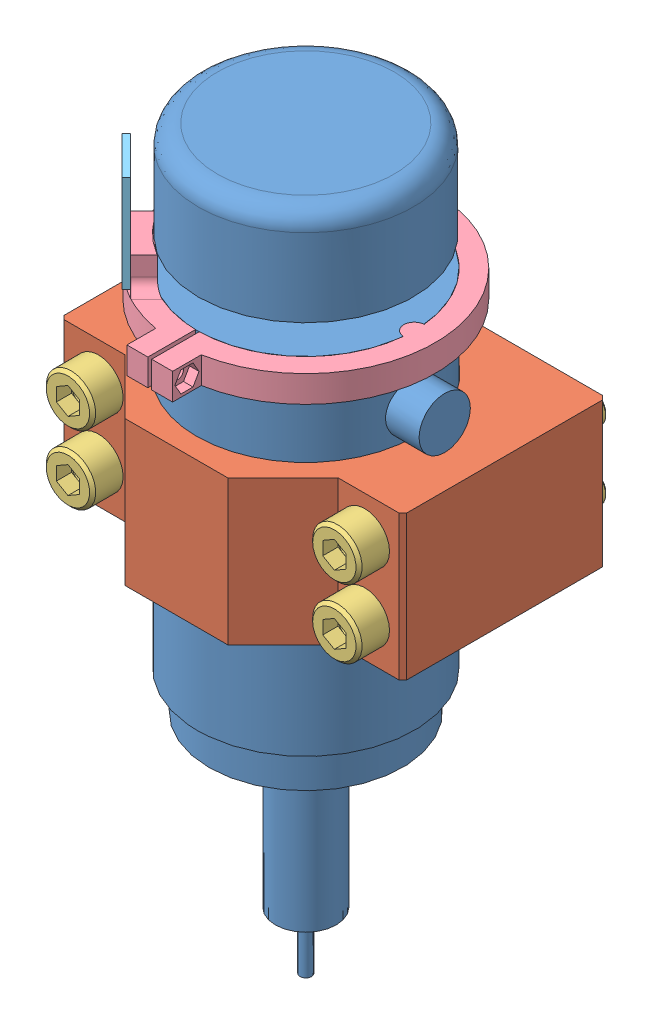
SolidWorks assembly Spindle Assembly, configuration Default. Lengths in mm.
Overall size (90 193.5 81.5).
8 component instances, 5 part files, 14 mates.
Components (placement in the parent):
- E240-Spindle-1: E240-Spindle [Default] at (-79.402 33.4299 34.999) size (73 193.5 57)
- Spindle-Clamp-1: Spindle-Clamp [Default] at (-79.402 35.9299 34.999) x (1 0 0) z (0 -1 0) size (90 68 38)
- socket head cap screw_am-1: socket head cap screw_am [B18.3.1M - 8 x 1.25 x 60 Hex SHCS -- 60NHX] at (-114.402 26.9299 62.499) x (0 0 -1) z (1 0 0) size (68 13 13)
- socket head cap screw_am-2: socket head cap screw_am [B18.3.1M - 8 x 1.25 x 60 Hex SHCS -- 60NHX] at (-114.402 44.9299 62.499) x (0 0 -1) z (1 0 0) size (68 13 13)
- socket head cap screw_am-3: socket head cap screw_am [B18.3.1M - 8 x 1.25 x 60 Hex SHCS -- 60NHX] at (-44.402 44.9299 62.499) x (0 0 -1) z (1 0 0) size (68 13 13)
- socket head cap screw_am-4: socket head cap screw_am [B18.3.1M - 8 x 1.25 x 60 Hex SHCS -- 60NHX] at (-44.402 26.9299 62.499) x (0 0 -1) z (1 0 0) size (68 13 13)
- Tachometer-Mount-1: Tachometer-Mount [Default] at (-79.402 71.9299 34.999) size (68 15 75)
- Tachometer-PCB-1: Tachometer-PCB [Default] at (-103.5839 91.8199 59.1809) x (-0.707107 0 -0.707107) z (0.707107 0 -0.707107) size (14.22 25.4 1.6)
Mates (geometry in assembly coordinates):
- Concentric3: concentric anti-aligned: circle of Spindle-Clamp-1; circle of E240-Spindle-1
- Distance3: distance = 29 mm aligned: plane of Spindle-Clamp-1 through (-79.402 16.9299 34.999) normal (0 -1 0); plane of E240-Spindle-1 through (-79.402 -12.0701 34.999) normal (0 -1 0)
- Concentric4: concentric aligned: cylinder of Spindle-Clamp-1 through (-114.402 26.9299 68.999) axis (0 0 1) radius 4.2; cylinder of socket head cap screw_am-1 through (-114.402 26.9299 94.249) axis (0 0 1) radius 6.5
- Coincident1: coincident anti-aligned: plane of Spindle-Clamp-1 through (-124.402 54.9299 54.499) normal (0 0 1); plane of socket head cap screw_am-1 through (-114.402 33.4299 54.499) normal (0 0 -1)
- Concentric5: concentric aligned: cylinder of Spindle-Clamp-1 through (-114.402 44.9299 68.999) axis (0 0 1) radius 4.2; cylinder of socket head cap screw_am-2 through (-114.402 44.9299 94.249) axis (0 0 1) radius 6.5
- Coincident2: coincident anti-aligned: plane of Spindle-Clamp-1 through (-124.402 54.9299 54.499) normal (0 0 1); plane of socket head cap screw_am-2 through (-114.402 51.4299 54.499) normal (0 0 -1)
- Concentric6: concentric aligned: cylinder of Spindle-Clamp-1 through (-44.402 44.9299 68.999) axis (0 0 1) radius 4.2; cylinder of socket head cap screw_am-3 through (-44.402 44.9299 94.249) axis (0 0 1) radius 6.5
- Coincident3: coincident anti-aligned: plane of Spindle-Clamp-1 through (-34.402 54.9299 54.499) normal (0 0 1); plane of socket head cap screw_am-3 through (-44.402 51.4299 54.499) normal (0 0 -1)
- Concentric7: concentric aligned: cylinder of Spindle-Clamp-1 through (-44.402 26.9299 68.999) axis (0 0 1) radius 4.2; cylinder of socket head cap screw_am-4 through (-44.402 26.9299 94.249) axis (0 0 1) radius 6.5
- Coincident4: coincident anti-aligned: plane of Spindle-Clamp-1 through (-34.402 54.9299 54.499) normal (0 0 1); plane of socket head cap screw_am-4 through (-44.402 33.4299 54.499) normal (0 0 -1)
- Concentric8: concentric aligned: circle of E240-Spindle-1; circle of Tachometer-Mount-1
- Coincident6: coincident aligned: plane of E240-Spindle-1 through (-79.402 78.9299 34.999) normal (0 1 0); plane of Tachometer-Mount-1 through (-79.402 78.9299 34.999) normal (0 1 0)
- Coincident7: coincident anti-aligned: plane of Tachometer-Mount-1 through (-107.4815 86.9299 53.0206) normal (-0.707107 0 0.707107); plane of Tachometer-PCB-1 through (-102.4526 91.8199 58.0495) normal (0.707107 0 -0.707107)
- Concentric9: concentric anti-aligned: circle of Tachometer-Mount-1; circle of Tachometer-PCB-1
